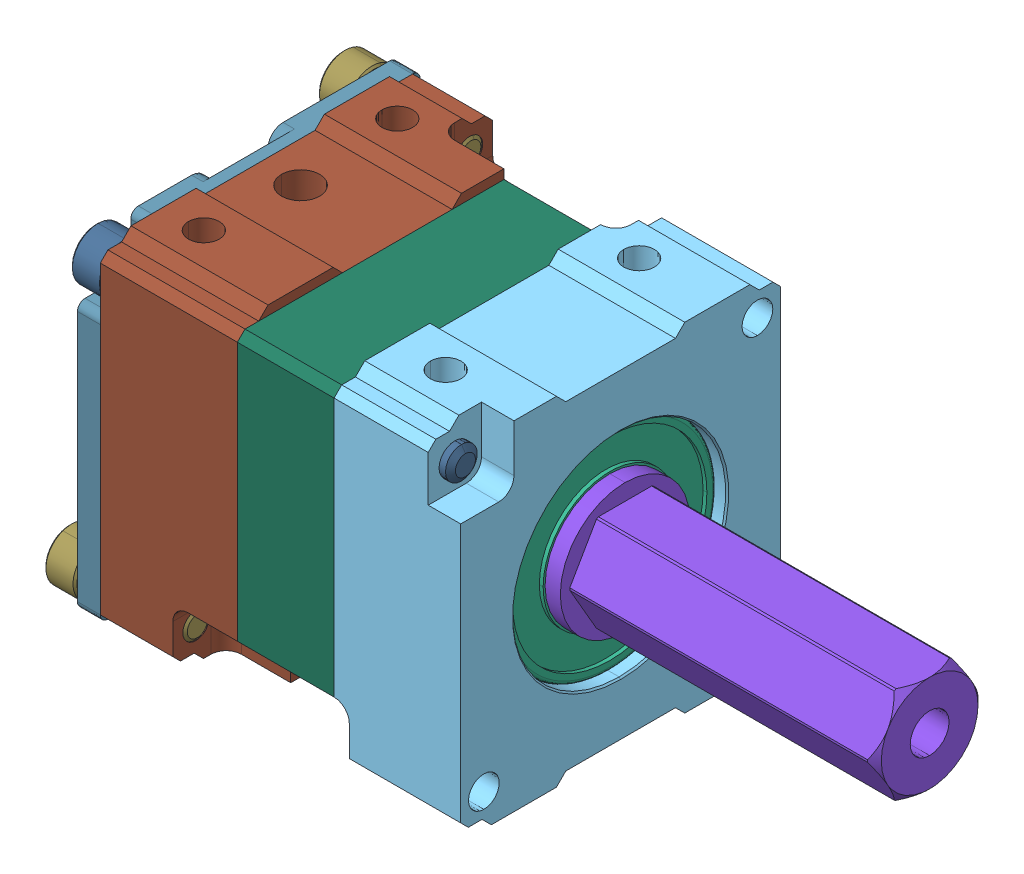
SolidWorks assembly VersaPlanetary_v2_Single_Stage_10_1_with_RS_550 (2), configuration Default. Lengths in mm.
Overall size (95.9 49.04 49.3).
29 component instances, 18 part files, 0 mates.
Components (placement in the parent):
- Copy (2) of VersaPlanetary_v2_Single_Stage_10_1_with_RS_550 (2)^VersaPlanetary_v2_Single_Stage_10_1_with_RS_550 (2)-1: Copy (2) of VersaPlanetary_v2_Single_Stage_10_1_with_RS_550 (2)^VersaPlanetary_v2_Single_Stage_10_1_with_RS_550 (2) [Default] at origin size (95.9 49.04 49.3) (virtual)
  - 217-2820 Rev1_Public(2)^Copy (2) of VersaPlanetary_v2_Single_Stage_10_1_with_RS_550 (2)_VersaPlanetary_v2_Single_Stage_10_1_with_RS_550 (2)-1: 217-2820 Rev1_Public(2)^Copy (2) of VersaPlanetary_v2_Single_Stage_10_1_with_RS_550 (2)_VersaPlanetary_v2_Single_Stage_10_1_with_RS_550 (2) [Default] at (-4.6546 22.225 0) x (0 -0.456494 0.889726) z (-1 0 0) size (39.22 38.88 17.4) (virtual)
    - 217-2625-100(2)^217-2820 Rev1_Public(2)_Copy (2) of VersaPlanetary_v2_Single_Stage_10_1_with_RS_550 (2)_VersaPlanetary_v2_Single_Stage_10_1_with_RS_550 (2)-1: 217-2625-100(2)^217-2820 Rev1_Public(2)_Copy (2) of VersaPlanetary_v2_Single_Stage_10_1_with_RS_550 (2)_VersaPlanetary_v2_Single_Stage_10_1_with_RS_550 (2) [Default] at origin size (39.22 38.88 12.7) (virtual)
      - 217-2625-008 Rev1(2)^217-2625-100(2)_217-2820 Rev1_Public(2)_Copy (2) of VersaPlanetary_v2_Single_Stage_10_1_with_RS_550 (2)_VersaPlanetary_v2_Single_Stage_10_1_with_RS_550 (2)-1: 217-2625-008 Rev1(2)^217-2625-100(2)_217-2820 Rev1_Public(2)_Copy (2) of VersaPlanetary_v2_Single_Stage_10_1_with_RS_550 (2)_VersaPlanetary_v2_Single_Stage_10_1_with_RS_550 (2) [Default] at origin size (34.7 34.7 4.7) (virtual)
      - 217-2625-010 Rev1(2)^217-2625-100(2)_217-2820 Rev1_Public(2)_Copy (2) of VersaPlanetary_v2_Single_Stage_10_1_with_RS_550 (2)_VersaPlanetary_v2_Single_Stage_10_1_with_RS_550 (2)-1: 217-2625-010 Rev1(2)^217-2625-100(2)_217-2820 Rev1_Public(2)_Copy (2) of VersaPlanetary_v2_Single_Stage_10_1_with_RS_550 (2)_VersaPlanetary_v2_Single_Stage_10_1_with_RS_550 (2) [Default] at (0 10.193 3.65) x (0.999813 0.019336 0) z (0 0 1) size (4 4 12) (virtual)
      - 217-2625-010 Rev1(2)^217-2625-100(2)_217-2820 Rev1_Public(2)_Copy (2) of VersaPlanetary_v2_Single_Stage_10_1_with_RS_550 (2)_VersaPlanetary_v2_Single_Stage_10_1_with_RS_550 (2)-2: 217-2625-010 Rev1(2)^217-2625-100(2)_217-2820 Rev1_Public(2)_Copy (2) of VersaPlanetary_v2_Single_Stage_10_1_with_RS_550 (2)_VersaPlanetary_v2_Single_Stage_10_1_with_RS_550 (2) [Default] at (8.691 -5.3258 3.65) size (4 4 12) (virtual)
      - 217-2625-010 Rev1(2)^217-2625-100(2)_217-2820 Rev1_Public(2)_Copy (2) of VersaPlanetary_v2_Single_Stage_10_1_with_RS_550 (2)_VersaPlanetary_v2_Single_Stage_10_1_with_RS_550 (2)-3: 217-2625-010 Rev1(2)^217-2625-100(2)_217-2820 Rev1_Public(2)_Copy (2) of VersaPlanetary_v2_Single_Stage_10_1_with_RS_550 (2)_VersaPlanetary_v2_Single_Stage_10_1_with_RS_550 (2) [Default] at (-8.691 -5.3258 3.65) size (4 4 12) (virtual)
      - 217-2625-005 Rev1_Planet_Revolving_Follower01(2)^217-2625-100(2)_217-2820 Rev1_Public(2)_Copy (2) of VersaPlanetary_v2_Single_Stage_10_1_with_RS_550 (2)_VersaPlanetary_v2_Single_Stage_10_1_wi~-1: 217-2625-005 Rev1_Planet_Revolving_Follower01(2)^217-2625-100(2)_217-2820 Rev1_Public(2)_Copy (2) of VersaPlanetary_v2_Single_Stage_10_1_with_RS_550 (2)_VersaPlanetary_v2_Single_Stage_10_1_wi~ [Default] at (8.691 -5.3258 6.35) x (0.932816 0.360354 0) z (0 0 1) size (16.89 16.89 8) (virtual)
      - 217-2625-005 Rev1_Planet_Revolving_Follower01(2)^217-2625-100(2)_217-2820 Rev1_Public(2)_Copy (2) of VersaPlanetary_v2_Single_Stage_10_1_with_RS_550 (2)_VersaPlanetary_v2_Single_Stage_10_1_wi~-2: 217-2625-005 Rev1_Planet_Revolving_Follower01(2)^217-2625-100(2)_217-2820 Rev1_Public(2)_Copy (2) of VersaPlanetary_v2_Single_Stage_10_1_with_RS_550 (2)_VersaPlanetary_v2_Single_Stage_10_1_wi~ [Default] at (-8.691 -5.3258 6.35) x (-0.932788 -0.360426 0) z (0 0 1) size (16.89 16.89 8) (virtual)
      - 217-2625-005 Rev1_Planet_Revolving_Follower01(2)^217-2625-100(2)_217-2820 Rev1_Public(2)_Copy (2) of VersaPlanetary_v2_Single_Stage_10_1_with_RS_550 (2)_VersaPlanetary_v2_Single_Stage_10_1_wi~-3: 217-2625-005 Rev1_Planet_Revolving_Follower01(2)^217-2625-100(2)_217-2820 Rev1_Public(2)_Copy (2) of VersaPlanetary_v2_Single_Stage_10_1_with_RS_550 (2)_VersaPlanetary_v2_Single_Stage_10_1_wi~ [Default] at (0 10.193 6.35) x (0.893583 0.448898 0) z (0 0 1) size (16.89 16.89 8) (virtual)
    - 217-2625-007 Rev1_Public(2)^217-2820 Rev1_Public(2)_Copy (2) of VersaPlanetary_v2_Single_Stage_10_1_with_RS_550 (2)_VersaPlanetary_v2_Single_Stage_10_1_with_RS_550 (2)-1: 217-2625-007 Rev1_Public(2)^217-2820 Rev1_Public(2)_Copy (2) of VersaPlanetary_v2_Single_Stage_10_1_with_RS_550 (2)_VersaPlanetary_v2_Single_Stage_10_1_with_RS_550 (2) [Default] at (0 0 6.7) x (0.992772 0.120019 0) z (0 0 1) size (15.27 15.27 12.7) (virtual)
  - 217-2625-026 Rev1(2)^Copy (2) of VersaPlanetary_v2_Single_Stage_10_1_with_RS_550 (2)_VersaPlanetary_v2_Single_Stage_10_1_with_RS_550 (2)-1: 217-2625-026 Rev1(2)^Copy (2) of VersaPlanetary_v2_Single_Stage_10_1_with_RS_550 (2)_VersaPlanetary_v2_Single_Stage_10_1_with_RS_550 (2) [Default] at (-6.5 22.225 0) x (0 -1 0) z (-1 0 0) size (44.45 42 18.12) (virtual)
  - 217-2742-001 Rev4(2)^Copy (2) of VersaPlanetary_v2_Single_Stage_10_1_with_RS_550 (2)_VersaPlanetary_v2_Single_Stage_10_1_with_RS_550 (2)-1: 217-2742-001 Rev4(2)^Copy (2) of VersaPlanetary_v2_Single_Stage_10_1_with_RS_550 (2)_VersaPlanetary_v2_Single_Stage_10_1_with_RS_550 (2) [Default] at (0.2002 22.225 0) x (1 0 0) z (0 -0.092627 0.995701) size (7 28 28) (virtual)
  - 217-2742-001 Rev4(2)^Copy (2) of VersaPlanetary_v2_Single_Stage_10_1_with_RS_550 (2)_VersaPlanetary_v2_Single_Stage_10_1_with_RS_550 (2)-2: 217-2742-001 Rev4(2)^Copy (2) of VersaPlanetary_v2_Single_Stage_10_1_with_RS_550 (2)_VersaPlanetary_v2_Single_Stage_10_1_with_RS_550 (2) [Default] at (8.2002 22.225 0) size (7 28 28) (virtual)
  - 217-2625-017 Rev1_9714K61(2)^Copy (2) of VersaPlanetary_v2_Single_Stage_10_1_with_RS_550 (2)_VersaPlanetary_v2_Single_Stage_10_1_with_RS_550 (2)-1: 217-2625-017 Rev1_9714K61(2)^Copy (2) of VersaPlanetary_v2_Single_Stage_10_1_with_RS_550 (2)_VersaPlanetary_v2_Single_Stage_10_1_with_RS_550 (2) [Default] at (7.42 22.3002 -0.342) x (0 0.56703 0.823697) z (0 -0.823697 0.56703) size (28.51 4.98 27.43) (virtual)
  - 217-2625-003 Rev1(2)^Copy (2) of VersaPlanetary_v2_Single_Stage_10_1_with_RS_550 (2)_VersaPlanetary_v2_Single_Stage_10_1_with_RS_550 (2)-1: 217-2625-003 Rev1(2)^Copy (2) of VersaPlanetary_v2_Single_Stage_10_1_with_RS_550 (2)_VersaPlanetary_v2_Single_Stage_10_1_with_RS_550 (2) [Default] at (7.4478 22.225 0) x (0 -1 0) z (1 0 0) size (17 17 64.11) (virtual)
  - 217-2625-018 Rev1_98541A410(2)^Copy (2) of VersaPlanetary_v2_Single_Stage_10_1_with_RS_550 (2)_VersaPlanetary_v2_Single_Stage_10_1_with_RS_550 (2)-1: 217-2625-018 Rev1_98541A410(2)^Copy (2) of VersaPlanetary_v2_Single_Stage_10_1_with_RS_550 (2)_VersaPlanetary_v2_Single_Stage_10_1_with_RS_550 (2) [Default] at (-0.7046 22.225 0) x (1 0 0) z (0 -0.017452 0.999848) size (1 19.6 17.4) (virtual)
  - 832-1750-Ring-Gear-Screw_SSA0832-0500ZC(2)^Copy (2) of VersaPlanetary_v2_Single_Stage_10_1_with_RS_550 (2)_VersaPlanetary_v2_Single_Stage_10_1_with_RS_550 (2)-1: 832-1750-Ring-Gear-Screw_SSA0832-0500ZC(2)^Copy (2) of VersaPlanetary_v2_Single_Stage_10_1_with_RS_550 (2)_VersaPlanetary_v2_Single_Stage_10_1_with_RS_550 (2) [Default] at (-30.7 4.725 -17.5) x (0 0.997447 0.071411) z (0 -0.071411 0.997447) size (6.73 48.51 6.73) (virtual)
  - 832-1750-Ring-Gear-Screw_SSA0832-0500ZC(2)^Copy (2) of VersaPlanetary_v2_Single_Stage_10_1_with_RS_550 (2)_VersaPlanetary_v2_Single_Stage_10_1_with_RS_550 (2)-2: 832-1750-Ring-Gear-Screw_SSA0832-0500ZC(2)^Copy (2) of VersaPlanetary_v2_Single_Stage_10_1_with_RS_550 (2)_VersaPlanetary_v2_Single_Stage_10_1_with_RS_550 (2) [Default] at (-30.7 39.725 17.5) x (0 0.005929 0.999982) z (0 -0.999982 0.005929) size (6.73 48.51 6.73) (virtual)
  - 217-2625-025 Rev1^Copy (2) of VersaPlanetary_v2_Single_Stage_10_1_with_RS_550 (2)_VersaPlanetary_v2_Single_Stage_10_1_with_RS_550 (2)-1: 217-2625-025 Rev1^Copy (2) of VersaPlanetary_v2_Single_Stage_10_1_with_RS_550 (2)_VersaPlanetary_v2_Single_Stage_10_1_with_RS_550 (2) [Default] at (-23.2 22.225 0) x (0 -1 0) z (-1 0 0) size (44.45 42 18) (virtual)
  - 217-4649-002 Rev1_SSA0832-0500ZC(2)^Copy (2) of VersaPlanetary_v2_Single_Stage_10_1_with_RS_550 (2)_VersaPlanetary_v2_Single_Stage_10_1_with_RS_550 (2)-1: 217-4649-002 Rev1_SSA0832-0500ZC(2)^Copy (2) of VersaPlanetary_v2_Single_Stage_10_1_with_RS_550 (2)_VersaPlanetary_v2_Single_Stage_10_1_with_RS_550 (2) [Default] at (-33.7 4.2645 17.9605) x (0 0.33842 -0.940995) z (0 0.940995 0.33842) size (6.73 16.76 6.73) (virtual)
  - 217-4649-002 Rev1_SSA0832-0500ZC(2)^Copy (2) of VersaPlanetary_v2_Single_Stage_10_1_with_RS_550 (2)_VersaPlanetary_v2_Single_Stage_10_1_with_RS_550 (2)-2: 217-4649-002 Rev1_SSA0832-0500ZC(2)^Copy (2) of VersaPlanetary_v2_Single_Stage_10_1_with_RS_550 (2)_VersaPlanetary_v2_Single_Stage_10_1_with_RS_550 (2) [Default] at (-33.7 40.1855 -17.9605) x (0 -0.308932 -0.951084) z (0 0.951084 -0.308932) size (6.73 16.76 6.73) (virtual)
  - 217-4649-005 Rev1_SSA0003-008BA^Copy (2) of VersaPlanetary_v2_Single_Stage_10_1_with_RS_550 (2)_VersaPlanetary_v2_Single_Stage_10_1_with_RS_550 (2)-1: 217-4649-005 Rev1_SSA0003-008BA^Copy (2) of VersaPlanetary_v2_Single_Stage_10_1_with_RS_550 (2)_VersaPlanetary_v2_Single_Stage_10_1_with_RS_550 (2) [Default] at (-30.7 22.225 -12.5) x (0 -0.5 0.866025) z (0 0.866025 0.5) size (5.5 11 5.5) (virtual)
  - 217-4649-005 Rev1_SSA0003-008BA^Copy (2) of VersaPlanetary_v2_Single_Stage_10_1_with_RS_550 (2)_VersaPlanetary_v2_Single_Stage_10_1_with_RS_550 (2)-2: 217-4649-005 Rev1_SSA0003-008BA^Copy (2) of VersaPlanetary_v2_Single_Stage_10_1_with_RS_550 (2)_VersaPlanetary_v2_Single_Stage_10_1_with_RS_550 (2) [Default] at (-30.7 22.225 12.5) x (0 -0.5 -0.866025) z (0 -0.866025 0.5) size (5.5 11 5.5) (virtual)
  - 217-2822-001 Rev4^Copy (2) of VersaPlanetary_v2_Single_Stage_10_1_with_RS_550 (2)_VersaPlanetary_v2_Single_Stage_10_1_with_RS_550 (2)-1: 217-2822-001 Rev4^Copy (2) of VersaPlanetary_v2_Single_Stage_10_1_with_RS_550 (2)_VersaPlanetary_v2_Single_Stage_10_1_with_RS_550 (2) [Default] at (-32.2 22.225 0) x (0 1 0) z (-1 0 0) size (42 42 4.8) (virtual)
  - 217-2816-001 Rev1(2)^Copy (2) of VersaPlanetary_v2_Single_Stage_10_1_with_RS_550 (2)_VersaPlanetary_v2_Single_Stage_10_1_with_RS_550 (2)-1: 217-2816-001 Rev1(2)^Copy (2) of VersaPlanetary_v2_Single_Stage_10_1_with_RS_550 (2)_VersaPlanetary_v2_Single_Stage_10_1_with_RS_550 (2) [Default] at (-6.35 22.225 0) x (0 -1 0) z (1 0 0) size (42 42 14.51) (virtual)
  - 217-4649-001 Rev1^Copy (2) of VersaPlanetary_v2_Single_Stage_10_1_with_RS_550 (2)_VersaPlanetary_v2_Single_Stage_10_1_with_RS_550 (2)-1: 217-4649-001 Rev1^Copy (2) of VersaPlanetary_v2_Single_Stage_10_1_with_RS_550 (2)_VersaPlanetary_v2_Single_Stage_10_1_with_RS_550 (2) [Default] at (-20.046 22.225 0) x (0 -1 0) z (1 0 0) size (18 18 13) (virtual)
  - 217-4649-007 Rev1_94105A824^Copy (2) of VersaPlanetary_v2_Single_Stage_10_1_with_RS_550 (2)_VersaPlanetary_v2_Single_Stage_10_1_with_RS_550 (2)-1: 217-4649-007 Rev1_94105A824^Copy (2) of VersaPlanetary_v2_Single_Stage_10_1_with_RS_550 (2)_VersaPlanetary_v2_Single_Stage_10_1_with_RS_550 (2) [Default] at (-25.521 22.225 -6.7835) x (-0.996104 -0.088191 0) z (0 0 -1) size (4.83 4.83 4.77) (virtual)
  - 217-2625-012 Rev1^Copy (2) of VersaPlanetary_v2_Single_Stage_10_1_with_RS_550 (2)_VersaPlanetary_v2_Single_Stage_10_1_with_RS_550 (2)-1: 217-2625-012 Rev1^Copy (2) of VersaPlanetary_v2_Single_Stage_10_1_with_RS_550 (2)_VersaPlanetary_v2_Single_Stage_10_1_with_RS_550 (2) [Default] at (-21.0318 22.225 0) x (0 0 1) z (-1 0 0) size (8.01 7.94 7.5) (virtual)
